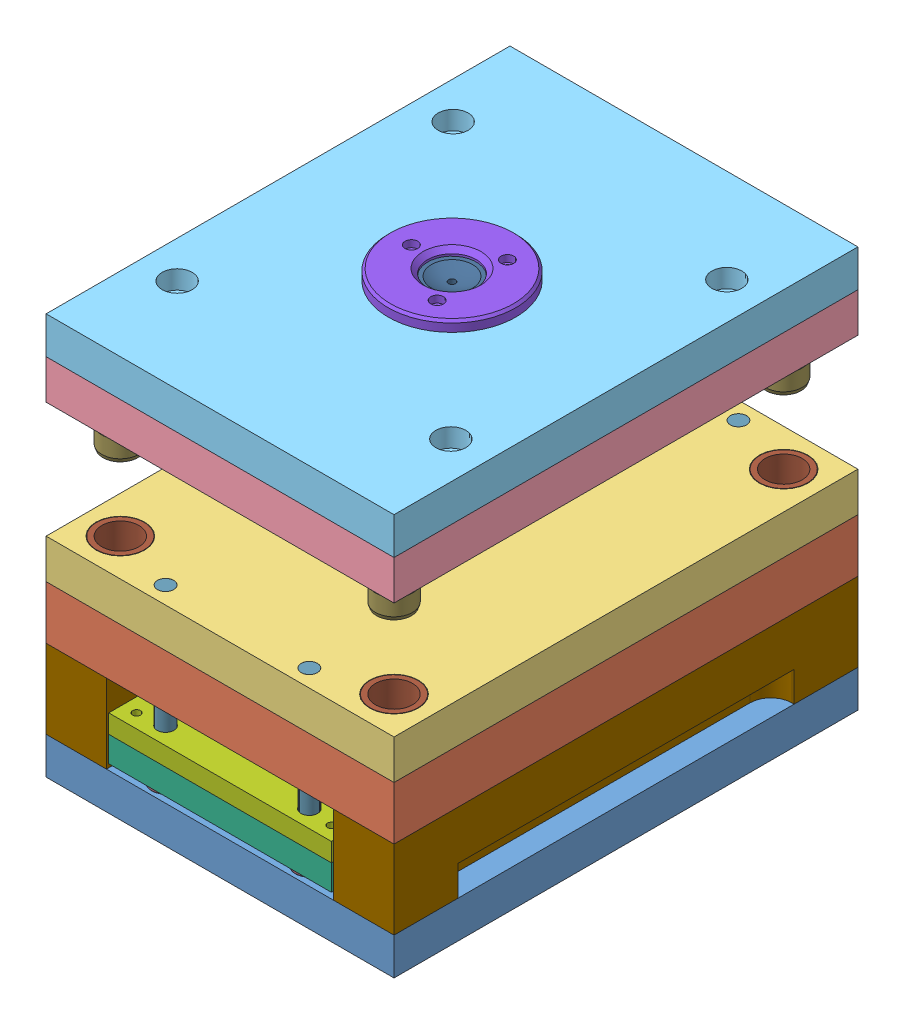
SolidWorks assembly Porta molde 300x400, configuration Valor predeterminado. Lengths in mm.
Overall size (300 355 401.07).
50 component instances, 17 part files, 54 mates.
Components (placement in the parent):
- Placa base inferior-1: Placa base inferior [Valor predeterminado] at (12.8367 -5.899 0) size (300 32 400)
- Placa suporte-1: Placa suporte [Valor predeterminado] at (12.8367 94.101 0) size (300 46 400)
- Placa cavidade P2-1: Placa cavidade P2 [Valor predeterminado] at (12.8367 140.101 0) size (300 34 400)
- Placa cavidade P1-1: Placa cavidade P1 [Valor predeterminado] at (12.8367 308.101 0) x (-1 0 0) z (0 0 1) size (300 34 400)
- Placa base superior-1: Placa base superior [Valor predeterminado] at (12.8367 340.101 0) x (-1 0 0) z (0 0 1) size (300 32 400)
- Placa extratora CPE-1: Placa extratora CPE [Valor predeterminado] at (12.8367 53.101 0) x (-1 0 0) z (0 0 1) size (192 22 400)
- Placa extratora PE-1: Placa extratora PE [Valor predeterminado] at (12.8367 53.101 0) size (192 16 400)
- Anel de centragem-1: Anel de centragem [Valor predeterminado] at (12.8367 337.101 0) x (0.5 0 0.866025) z (-0.866025 0 0.5) size (110 12 110)
- Espaçador-3: Espaçador [Valor predeterminado] at (110.8367 94.101 200) x (1 0 0) z (0 0 -1) size (52 68 400)
- Espaçador-4: Espaçador [Valor predeterminado] at (-85.1633 94.101 -200) x (-1 0 0) z (0 0 1) size (52 68 400)
- Socket Head Cap Screw_ISO-3: Socket Head Cap Screw_ISO [ISO 4762 M6 x 25 --- 25N] at (30.3367 349.101 -30.3109) x (0 -1 0) z (0.216767 0 0.976223) (suppressed, hidden)
- Socket Head Cap Screw_ISO-4: Socket Head Cap Screw_ISO [ISO 4762 M6 x 25 --- 25N] at (-22.1633 349.101 0) x (0 -1 0) z (0.737051 0 -0.675837) (suppressed, hidden)
- Socket Head Cap Screw_ISO-5: Socket Head Cap Screw_ISO [ISO 4762 M6 x 25 --- 25N] at (30.3367 349.101 30.3109) x (0 -1 0) z (-0.953818 0 -0.300386) (suppressed, hidden)
- Bico-1: Bico [Valor predeterminado] at (12.8367 274.101 0) size (48 69 48)
- Socket Head Cap Screw_ISO-6: Socket Head Cap Screw_ISO [ISO 4762 M16 x 30 --- 30N] at (130.8367 340.101 -119) x (0 -1 0) z (0 0 1) (suppressed, hidden)
- Bucha-1: Bucha [B16] at (130.8367 140.101 168) x (0 1 0) z (0 0 1) size (34 48 48)
- Socket Head Cap Screw_ISO-7: Socket Head Cap Screw_ISO [ISO 4762 M16 x 30 --- 30N] at (130.8367 340.101 119) x (0 -1 0) z (0 0 1) (suppressed, hidden)
- Socket Head Cap Screw_ISO-8: Socket Head Cap Screw_ISO [ISO 4762 M16 x 30 --- 30N] at (-105.1633 340.101 -119) x (0 -1 0) z (0 0 1) (suppressed, hidden)
- Socket Head Cap Screw_ISO-9: Socket Head Cap Screw_ISO [ISO 4762 M16 x 30 --- 30N] at (-105.1633 340.101 119) x (0 -1 0) z (0 0 1) (suppressed, hidden)
- Socket Head Cap Screw_ISO-10: Socket Head Cap Screw_ISO [ISO 4762 M16 x 150 --- 44N] at (130.8367 -5.899 -119) x (0 1 0) z (0 0 1) (suppressed, hidden)
- Socket Head Cap Screw_ISO-11: Socket Head Cap Screw_ISO [ISO 4762 M16 x 150 --- 44N] at (130.8367 -5.899 119) x (0 1 0) z (0 0 1) (suppressed, hidden)
- Socket Head Cap Screw_ISO-12: Socket Head Cap Screw_ISO [ISO 4762 M16 x 150 --- 44N] at (-105.1633 -5.899 -119) x (0 1 0) z (0 0 1) (suppressed, hidden)
- Socket Head Cap Screw_ISO-13: Socket Head Cap Screw_ISO [ISO 4762 M16 x 150 --- 44N] at (-105.1633 -5.899 119) x (0 1 0) z (0 0 1) (suppressed, hidden)
- Pino-1: Pino [C46] at (130.8367 308.101 168) x (0 -1 0) z (0.180366 0 0.9836) size (68 48 48)
- Pino-2: Pino [C46] at (130.8367 308.101 -168) x (0 -1 0) z (0.180366 0 0.9836) size (68 48 48)
- Pino-3: Pino [C46] at (-105.1633 308.101 168) x (0 -1 0) z (0.180366 0 0.9836) size (68 48 48)
- Pino-4: Pino [C46] at (-105.1633 308.101 -168) x (0 -1 0) z (0.180366 0 0.9836) size (68 48 48)
- Bucha-2: Bucha [B16] at (130.8367 140.101 -168) x (0 1 0) z (0 0 1) size (34 48 48)
- Bucha-3: Bucha [B16] at (-105.1633 140.101 168) x (0 1 0) z (0 0 1) size (34 48 48)
- Bucha-4: Bucha [B16] at (-105.1633 140.101 -168) x (0 1 0) z (0 0 1) size (34 48 48)
- Socket Head Cap Screw_ISO-14: Socket Head Cap Screw_ISO [ISO 4762 M8 x 25 --- 25N] at (-71.1633 31.101 188) x (0 1 0) z (0 0 1) (suppressed, hidden)
- Socket Head Cap Screw_ISO-15: Socket Head Cap Screw_ISO [ISO 4762 M8 x 25 --- 25N] at (-71.1633 31.101 -188) x (0 1 0) z (0 0 1) (suppressed, hidden)
- Socket Head Cap Screw_ISO-16: Socket Head Cap Screw_ISO [ISO 4762 M8 x 25 --- 25N] at (96.8367 31.101 188) x (0 1 0) z (0 0 1) (suppressed, hidden)
- Socket Head Cap Screw_ISO-17: Socket Head Cap Screw_ISO [ISO 4762 M8 x 25 --- 25N] at (96.8367 31.101 -188) x (0 1 0) z (0 0 1) (suppressed, hidden)
- PA 02-1: PA 02 [Valor predeterminado] at (-49.1633 11.101 185) size (24 20 24)
- PA 02-2: PA 02 [Valor predeterminado] at (-49.1633 11.101 -185) size (24 20 24)
- PA 02-3: PA 02 [Valor predeterminado] at (74.8367 11.101 185) size (24 20 24)
- PA 02-4: PA 02 [Valor predeterminado] at (74.8367 11.101 -185) size (24 20 24)
- Extrator-1: Extrator [Valor predeterminado] at (-49.1633 53.101 185) x (0.670266 0 -0.742121) z (0.742121 0 0.670266) size (22 121 22)
- Extrator-2: Extrator [Valor predeterminado] at (-49.1633 53.101 -185) x (0.670266 0 -0.742121) z (0.742121 0 0.670266) size (22 121 22)
- Extrator-3: Extrator [Valor predeterminado] at (74.8367 53.101 185) x (0.670266 0 -0.742121) z (0.742121 0 0.670266) size (22 121 22)
- Extrator-4: Extrator [Valor predeterminado] at (74.8367 53.101 -185) x (0.670266 0 -0.742121) z (0.742121 0 0.670266) size (22 121 22)
- Bucha 2-1: Bucha 2 [Valor predeterminado] at (83.8367 31.101 153) x (0 1 0) z (0 0 1) size (38 38.1 38.1)
- Pino 2-1: Pino 2 [Valor predeterminado] at (83.8367 -5.899 153) x (0 1 0) z (0 0 1) size (102 38 38)
- Bucha 2-2: Bucha 2 [Valor predeterminado] at (83.8367 31.101 -153) x (0 1 0) z (0 0 1) size (38 38.1 38.1)
- Bucha 2-3: Bucha 2 [Valor predeterminado] at (-58.1633 31.101 153) x (0 1 0) z (0 0 1) size (38 38.1 38.1)
- Bucha 2-4: Bucha 2 [Valor predeterminado] at (-58.1633 31.101 -153) x (0 1 0) z (0 0 1) size (38 38.1 38.1)
- Pino 2-2: Pino 2 [Valor predeterminado] at (83.8367 -5.899 -153) x (0 1 0) z (0 0 1) size (102 38 38)
- Pino 2-3: Pino 2 [Valor predeterminado] at (-58.1633 -5.899 153) x (0 1 0) z (0 0 1) size (102 38 38)
- Pino 2-4: Pino 2 [Valor predeterminado] at (-58.1633 -5.899 -153) x (0 1 0) z (0 0 1) size (102 38 38)
Mates (geometry in assembly coordinates):
- Coincidente11: coincident anti-aligned: plane of Placa suporte-1 through (-137.1633 140.101 200) normal (0 1 0); plane of Placa cavidade P2-1 through (-137.1633 140.101 200) normal (0 -1 0)
- Coincidente12: coincident aligned: plane of Placa suporte-1 through (-137.1633 140.101 200) normal (0 0 1); plane of Placa cavidade P2-1 through (-137.1633 174.101 200) normal (0 0 1)
- Coincidente13: coincident aligned: plane of Placa suporte-1 through (162.8367 140.101 -200) normal (1 0 0); plane of Placa cavidade P2-1 through (162.8367 174.101 -200) normal (1 0 0)
- Distância1: distance = 100 mm anti-aligned: plane of Placa cavidade P2-1 through (-137.1633 174.101 200) normal (0 1 0); plane of Placa cavidade P1-1 through (162.8367 274.101 200) normal (0 -1 0)
- Coincidente15: coincident aligned: plane of Placa cavidade P2-1 through (162.8367 174.101 -200) normal (1 0 0); plane of Placa cavidade P1-1 through (162.8367 274.101 -200) normal (1 0 0)
- Coincidente16: coincident aligned: plane of Placa cavidade P2-1 through (-137.1633 174.101 200) normal (0 0 1); plane of Placa cavidade P1-1 through (162.8367 274.101 200) normal (0 0 1)
- Coincidente17: coincident anti-aligned: plane of Placa cavidade P1-1 through (162.8367 308.101 200) normal (0 1 0); plane of Placa base superior-1 through (162.8367 308.101 200) normal (0 -1 0)
- Coincidente18: coincident aligned: plane of Placa cavidade P1-1 through (162.8367 274.101 -200) normal (1 0 0); plane of Placa base superior-1 through (162.8367 308.101 -200) normal (1 0 0)
- Coincidente19: coincident aligned: plane of Placa cavidade P1-1 through (162.8367 274.101 200) normal (0 0 1); plane of Placa base superior-1 through (162.8367 308.101 200) normal (0 0 1)
- Paralelo1: parallel anti-aligned: plane of Placa base inferior-1 through (-137.1633 26.101 200) normal (0 1 0); plane of Placa extratora CPE-1 through (108.8367 31.101 200) normal (0 -1 0)
- Coincidente21: coincident aligned: plane of Placa base inferior-1 through (-137.1633 26.101 200) normal (0 0 1); plane of Placa extratora CPE-1 through (108.8367 31.101 200) normal (0 0 1)
- Coincidente22: coincident anti-aligned: plane of Placa extratora CPE-1 through (108.8367 53.101 200) normal (0 1 0); plane of Placa extratora PE-1 through (-83.1633 53.101 200) normal (0 -1 0)
- Coincidente23: coincident aligned: plane of Placa extratora CPE-1 through (108.8367 31.101 -200) normal (1 0 0); plane of Placa extratora PE-1 through (108.8367 69.101 -200) normal (1 0 0)
- Coincidente24: coincident aligned: plane of Placa extratora CPE-1 through (108.8367 31.101 200) normal (0 0 1); plane of Placa extratora PE-1 through (-83.1633 69.101 200) normal (0 0 1)
- Coincidente26: coincident anti-aligned: plane of Placa base superior-1 through (12.8367 337.101 0) normal (0 1 0); plane of Anel de centragem-1 through (31.8367 337.101 32.909) normal (0 -1 0)
- Coincidente27: coincident anti-aligned: circle of Placa base superior-1; cylinder of Anel de centragem-1 through (12.8367 337.101 0) axis (0 -1 0) radius 45
- Coincidente28: coincident anti-aligned: plane of Placa base inferior-1 through (-137.1633 26.101 200) normal (0 1 0); plane of Espaçador-3 through (110.8367 26.101 -200) normal (0 -1 0)
- Coincidente29: coincident aligned: plane of Placa base inferior-1 through (-137.1633 26.101 200) normal (0 0 1); plane of Espaçador-3 through (110.8367 26.101 200) normal (0 0 1)
- Coincidente30: coincident aligned: plane of Placa base inferior-1 through (162.8367 26.101 -200) normal (1 0 0); plane of Espaçador-3 through (162.8367 94.101 -200) normal (1 0 0)
- Coincidente31: coincident anti-aligned: plane of Placa suporte-1 through (-137.1633 94.101 200) normal (0 -1 0); plane of Espaçador-3 through (110.8367 94.101 -200) normal (0 1 0)
- Coincidente32: coincident aligned: plane of Placa suporte-1 through (162.8367 140.101 -200) normal (1 0 0); plane of Espaçador-3 through (162.8367 94.101 -200) normal (1 0 0)
- Coincidente33: coincident aligned: plane of Placa suporte-1 through (-137.1633 140.101 200) normal (0 0 1); plane of Espaçador-3 through (110.8367 26.101 200) normal (0 0 1)
- Coincidente34: coincident aligned: plane of Placa base inferior-1 through (-137.1633 26.101 -200) normal (-1 0 0); plane of Espaçador-4 through (-137.1633 94.101 200) normal (-1 0 0)
- Coincidente35: coincident aligned: plane of Placa base inferior-1 through (-137.1633 26.101 200) normal (0 0 1); plane of Espaçador-4 through (-85.1633 26.101 200) normal (0 0 1)
- Coincidente36: coincident anti-aligned: plane of Placa suporte-1 through (-137.1633 94.101 200) normal (0 -1 0); plane of Espaçador-4 through (-85.1633 94.101 200) normal (0 1 0)
- Concêntrico1: concentric aligned: cylinder of Placa base superior-1 through (30.3367 337.101 -30.3109) axis (0 1 0) radius 2.5; cylinder of Anel de centragem-1 through (30.3367 349.101 -30.3109) axis (0 1 0) radius 3.3
- Concêntrico2: concentric aligned: cylinder of Anel de centragem-1; cylinder of Socket Head Cap Screw_ISO-3
- Coincidente37: coincident anti-aligned: plane of Anel de centragem-1; plane of Socket Head Cap Screw_ISO-3
- Coincidente38: coincident anti-aligned: plane of Placa cavidade P1-1 through (162.8367 308.101 200) normal (0 1 0); plane of Bico-1 through (24.8367 308.101 0) normal (0 -1 0)
- Concêntrico3: concentric anti-aligned: cylinder of Placa cavidade P1-1 through (12.8367 274.101 0) axis (0 1 0) radius 13; cylinder of Bico-1 through (12.8367 274.101 0) axis (0 -1 0) radius 13
- Coincidente39: coincident anti-aligned: plane of Placa base superior-1; plane of Socket Head Cap Screw_ISO-6
- Concêntrico4: concentric aligned: cylinder of Placa base superior-1; cylinder of Socket Head Cap Screw_ISO-6
- Coincidente40: coincident anti-aligned: plane of Placa cavidade P2-1 through (151.8367 148.101 168) normal (0 -1 0); plane of Bucha-1 through (106.8367 148.101 168) normal (0 1 0)
- Concêntrico5: concentric aligned: cylinder of Placa cavidade P2-1 through (130.8367 140.101 168) axis (0 -1 0) radius 21; cylinder of Bucha-1 through (130.8367 1.1757 168) axis (0 -1 0) radius 21
- Coincidente43: coincident anti-aligned: plane of Placa base inferior-1; plane of Socket Head Cap Screw_ISO-10
- Concêntrico8: concentric aligned: cylinder of Placa base inferior-1; cylinder of Socket Head Cap Screw_ISO-10
- Coincidente44: coincident anti-aligned: plane of Placa cavidade P1-1 through (109.8367 300.101 168) normal (0 1 0); plane of Pino-1 through (151.4923 300.101 164.2123) normal (0 -1 0)
- Concêntrico9: concentric anti-aligned: cylinder of Placa cavidade P1-1 through (130.8367 308.101 168) axis (0 1 0) radius 21; cylinder of Pino-1 through (130.8367 104.8026 168) axis (0 -1 0) radius 21
- Coincidente45: coincident anti-aligned: plane of Placa extratora CPE-1; plane of Socket Head Cap Screw_ISO-14
- Concêntrico10: concentric aligned: cylinder of Placa extratora CPE-1; cylinder of Socket Head Cap Screw_ISO-14
- Concêntrico11: concentric anti-aligned: cylinder of Placa base inferior-1 through (-49.1633 26.101 185) axis (0 1 0) radius 7; cylinder of PA 02-1 through (-49.1633 11.101 185) axis (0 -1 0) radius 7
- Coincidente46: coincident anti-aligned: plane of Placa base inferior-1 through (-137.1633 26.101 200) normal (0 1 0); plane of PA 02-1 through (-37.1633 26.101 185) normal (0 -1 0)
- Paralelo2: parallel anti-aligned: plane of Placa extratora CPE-1 through (108.8367 31.101 200) normal (0 -1 0); plane of PA 02-1 through (-49.1633 31.101 185) normal (0 1 0)
- Concêntrico12: concentric aligned: cylinder of Placa extratora PE-1 through (-49.1633 53.101 185) axis (0 -1 0) radius 7.25; cylinder of Extrator-1 through (-49.1633 53.101 185) axis (0 -1 0) radius 7
- Coincidente48: coincident anti-aligned: plane of Placa extratora CPE-1 through (108.8367 53.101 200) normal (0 1 0); plane of Extrator-1 through (-41.7904 53.101 176.8367) normal (0 -1 0)
- Concêntrico13: concentric aligned: cylinder of Placa cavidade P2-1 through (74.8367 140.101 185) axis (0 -1 0) radius 7; cylinder of Extrator-3 through (74.8367 53.101 185) axis (0 -1 0) radius 7
- Concêntrico14: concentric aligned: cylinder of Placa extratora PE-1 through (74.8367 53.101 185) axis (0 -1 0) radius 7.25; cylinder of Extrator-3 through (74.8367 53.101 185) axis (0 -1 0) radius 7
- Coincidente49: coincident anti-aligned: plane of Placa extratora CPE-1 through (67.8367 46.101 153) normal (0 1 0); plane of Bucha 2-1 through (67.8367 46.101 153) normal (0 -1 0)
- Concêntrico15: concentric anti-aligned: cylinder of Placa extratora CPE-1 through (83.8367 53.101 153) axis (0 1 0) radius 16; cylinder of Bucha 2-1 through (83.8367 -59.5152 153) axis (0 -1 0) radius 16
- Coincidente50: coincident aligned: plane of Placa base inferior-1 through (-137.1633 -5.899 200) normal (0 -1 0); plane of Pino 2-1 through (83.8367 -5.899 153) normal (0 -1 0)
- Concêntrico16: concentric aligned: cylinder of Placa base inferior-1 through (83.8367 -5.899 153) axis (0 -1 0) radius 16; cylinder of Pino 2-1 through (83.8367 -159.3058 153) axis (0 -1 0) radius 16
- LimitDistance1: limit distance = 0 mm aligned: plane of Placa cavidade P2-1 through (-137.1633 174.101 200) normal (0 1 0); plane of Extrator-1 through (-49.1633 174.101 185) normal (0 1 0)
- LocalLPattern3: unknown: line of Placa extratora CPE-1 through (108.8367 31.101 200) axis (-1 0 0); line of Placa extratora CPE-1 through (108.8367 31.101 -200) axis (0 0 1)
- LocalLPattern4: unknown: line of Placa base inferior-1 through (-137.1633 26.101 200) axis (1 0 0); line of Placa base inferior-1 through (162.8367 26.101 200) axis (0 0 -1)
